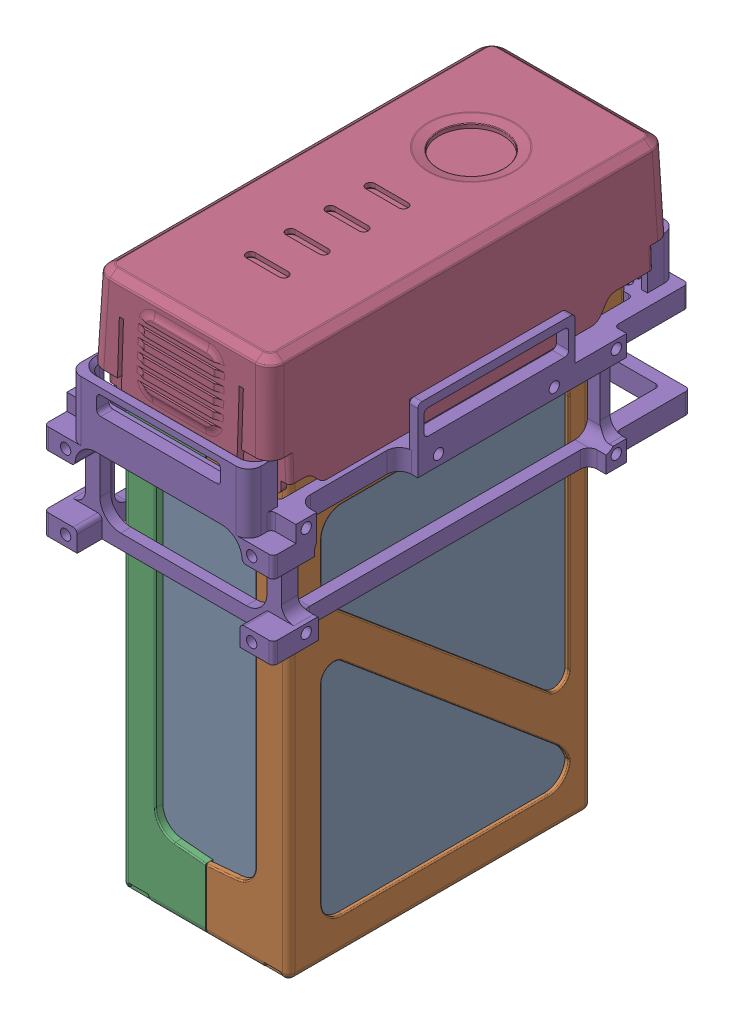
SolidWorks assembly 电池 2020-10-24o, configuration 默认. Lengths in mm.
Overall size (55.4 133.51 103.5).
5 component instances, 5 part files, 17 mates.
Components (placement in the parent):
- 电池（中）2019-10-19o-1: 电池（中）2019-10-19o [默认] at (8.9743 7.621 106.0001) size (37 106 68)
- 电池（右）2019-10-19o-1: 电池（右）2019-10-19o [默认] at (19.0243 10.321 107.3001) x (0 -1 0) z (0 0 -1) size (118.5 22.62 87)
- 电池（左） 2019-10-19o-1: 电池（左） 2019-10-19o [默认] at (-1.0757 10.321 107.3001) x (0 -1 0) z (0 0 1) size (118.51 20.13 87.01)
- 电池（上）2019-10-19o-1: 电池（上）2019-10-19o [默认] at (9.4233 56.821 101.9501) x (0 0 -1) z (0 1 0) size (101.5 44.3 30)
- 电池架2020-10-25o-2: 电池架2020-10-25o [默认] at (8.3743 55.6176 102.8812) x (0 0 -1) z (0 1 0) size (103.5 55.4 37.5)
Mates (geometry in assembly coordinates):
- 距离2: distance = 0.6 mm anti-aligned: plane of 电池（中）2019-10-19-1 through (27.4743 60.621 72.0001) normal (1 0 0); plane of 电池（右）2019-10-19-1 through (28.0743 62.521 73.0001) normal (-1 0 0)
- 重合2: coincident anti-aligned: plane of 电池（中）2019-10-19-1 through (27.4743 60.621 72.0001) normal (0 0 -1); plane of 电池（右）2019-10-19-1 through (8.9743 -46.679 72.0001) normal (0 0 1)
- 重合3: coincident anti-aligned: plane of 电池（中）2019-10-19-1 through (8.9743 -45.379 106.0001) normal (0 -1 0); plane of 电池（右）2019-10-19-1 through (8.9743 -45.379 143.9001) normal (0 1 0)
- 重合4: coincident aligned: plane of 电池（右）2019-10-19-1 through (27.5743 68.821 142.4001) normal (0 1 0); plane of 电池（左） 2019-10-19-1 through (-9.6257 68.821 60.8001) normal (0 1 0)
- 重合5: coincident aligned: plane of 电池（右）2019-10-19-1 through (8.9743 -46.679 143.9001) normal (0 0 1); plane of 电池（左） 2019-10-19-1 through (8.9743 -46.679 143.9001) normal (0 0 1)
- 距离1: distance = 0.6 mm anti-aligned: plane of 电池（中）2019-10-19-1 through (-9.5257 60.621 72.0001) normal (-1 0 0); plane of 电池（左） 2019-10-19-1 through (-10.1257 -43.879 141.1001) normal (1 0 0)
- 重合7: coincident anti-aligned: plane of 电池（右）2019-10-19-1 through (27.5743 68.821 142.4001) normal (0 1 0); plane of 电池（上）2019-10-19-1 through (9.4233 68.821 101.9501) normal (0 -1 0)
- 重合9: coincident: plane of 电池（左） 2019-10-19-1 through (-11.1257 10.321 107.3001) normal (-1 0 0); line of 电池（上）2019-10-19-1 through (-11.1257 56.821 73.1856) axis (0 0 1)
- 重合10: coincident anti-aligned: plane of 电池（左） 2019-10-19-1 through (-9.6257 68.821 60.8001) normal (0 1 0); plane of 电池（上）2019-10-19-1 through (9.4233 68.821 101.9501) normal (0 -1 0)
- 重合12: coincident: plane of 电池（右）2019-10-19-1 through (19.0243 10.321 59.3001) normal (0 0 -1); line of 电池（上）2019-10-19-1 through (-10.4717 61.221 59.3001) axis (1 0 0)
- 平行1: parallel: plane of 电池（上）2019-10-19-1 through (9.4233 86.821 101.9501) normal (0 1 0); plane of 电池架2019-12-27-1 through (-17.7257 56.821 55.6149) normal (0 1 0)
- 宽度1: width: plane of 电池架2019-12-27-1 through (-11.7257 29.821 148.6149) normal (1 0 0); plane of 电池（右）2019-10-19-1 through (29.6743 29.821 148.6149) normal (-1 0 0); plane of 电池架2019-12-27-1 through (29.0743 10.321 107.3001) normal (1 0 0); plane of 电池（左） 2019-10-19-1 through (-11.1257 10.321 107.3001) normal (-1 0 0)
- 重合16: coincident: plane of 电池（上）2019-10-19-1 through (9.4233 56.821 101.9501) normal (0 -1 0); plane of 电池架2019-12-27-1 through (-17.7257 56.821 55.6149) normal (0 1 0)
- 宽度2: width: plane of 电池（上）2019-10-19-1 through (9.4233 56.821 51.2001) normal (0 0 -1); plane of 电池架2019-12-27-1 through (9.4233 56.821 152.7001) normal (0 0 1); plane of 电池（上）2019-10-19-1 through (-17.7257 29.821 153.7001) normal (0 0 1); plane of 电池架2019-12-27-1 through (-17.7257 29.821 50.2001) normal (0 0 -1)
- 重合17: coincident anti-aligned: plane of 电池（右）2019-10-19-1 through (19.0243 10.321 60.0001) normal (0 0 -1); plane of 电池架2020-10-25-1 through (25.6243 55.0649 60.0001) normal (0 0 1)
- 重合18: coincident anti-aligned: plane of 电池（右）2019-10-19-1 through (29.0743 10.321 107.3001) normal (1 0 0); plane of 电池架2020-10-25-1 through (29.0743 17.5649 151.0001) normal (-1 0 0)
- 重合24: coincident anti-aligned: plane of 电池（右）2019-10-19-1 through (29.0743 10.321 107.3001) normal (1 0 0); plane of 电池架2020-10-25-2 through (29.0743 28.6176 145.1312) normal (-1 0 0)
